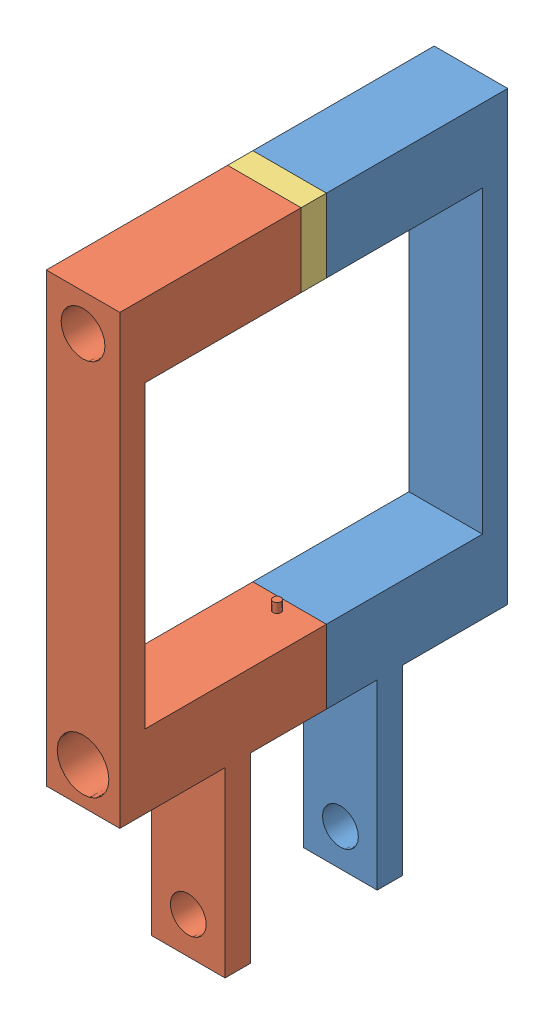
SolidWorks assembly Assem1, configuration Default. Lengths in mm.
Overall size (13.84 118.41 73.02).
3 component instances, 3 part files, 7 mates.
Components (placement in the parent):
- LeftSide-1: LeftSide [Default] at (-28.916 -52.7159 9.9423) size (13.84 118.41 34.13)
- RightSide-1: RightSide [Default] at (-15.073 -52.7159 43.3433) x (-1 0 0) z (0 0 -1) size (13.84 118.41 38.89)
- Manual_Pin-1: Manual_Pin [Default] at (-15.073 51.8559 24.2616) x (-1 0 0) z (0 0 1) size (13.84 16 4.76)
Mates (geometry in assembly coordinates):
- Coincident1: coincident aligned: cylinder of LeftSide-1 through (-21.9945 -11.5044 26.8651) axis (0 0 -1) radius 2.5527; circle of RightSide-1
- Concentric1: concentric anti-aligned: circle of LeftSide-1; circle of RightSide-1
- Concentric2: concentric anti-aligned: circle of LeftSide-1; circle of RightSide-1
- Coincident4: coincident anti-aligned: plane of LeftSide-1 through (-28.916 -52.7159 24.2616) normal (0 0 1); plane of RightSide-1 through (-15.073 -52.7159 24.2616) normal (0 0 -1)
- Coincident5: coincident anti-aligned: plane of RightSide-1 through (-15.073 -52.7159 29.0241) normal (0 0 -1); plane of Manual_Pin-1 through (-15.073 51.8559 29.0241) normal (0 0 1)
- Coincident6: coincident anti-aligned: plane of LeftSide-1 through (-28.916 -52.7159 24.2616) normal (0 0 1); plane of Manual_Pin-1 through (-15.073 51.8559 24.2616) normal (0 0 -1)
- Coincident7: coincident aligned: plane of LeftSide-1 through (-28.916 65.6989 9.9423) normal (0 1 0); plane of Manual_Pin-1 through (-15.073 65.6989 29.0241) normal (0 1 0)
